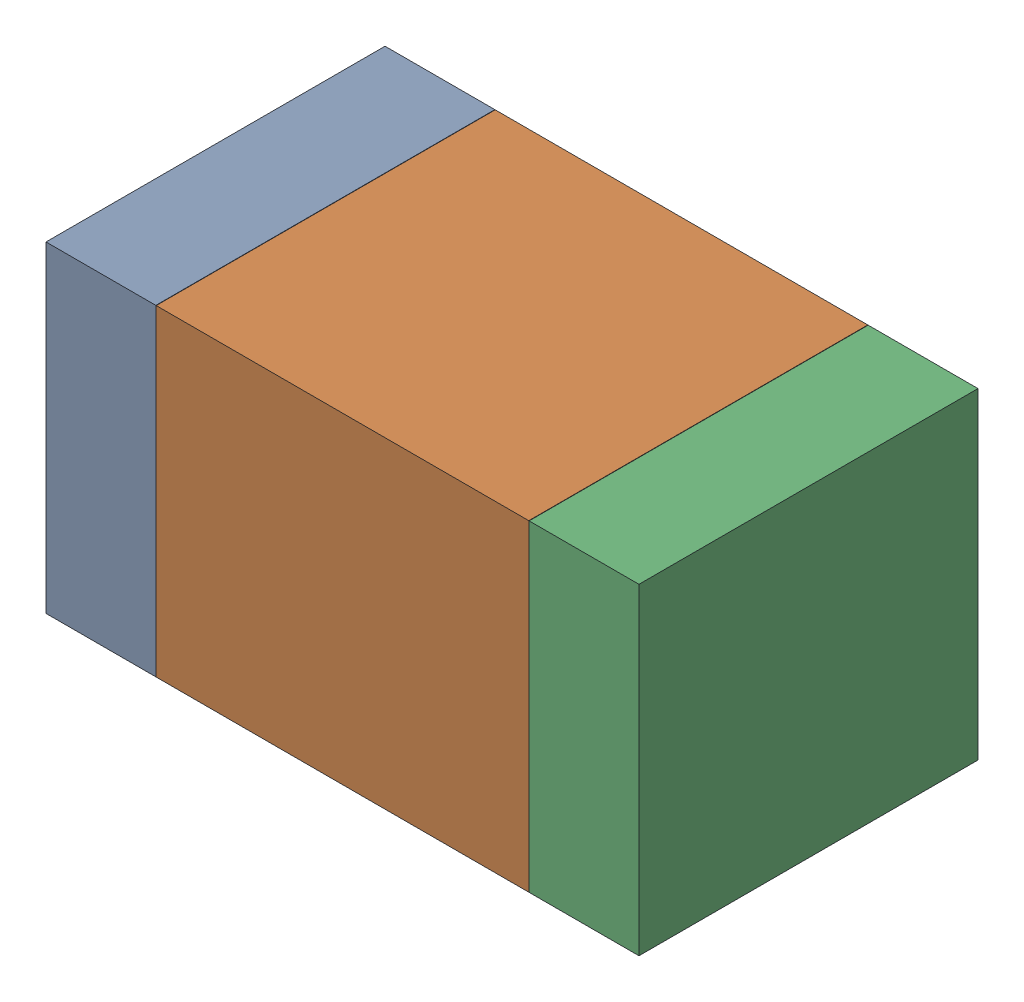
SolidWorks assembly R36, configuration Default. Lengths in mm.
Overall size (1.75 0.95 1).
6 component instances, 2 part files, 0 mates.
Components (placement in the parent):
- 6575498272-1: 6575498272 [Default] at (43.3565 24.638 0) size (0.32 0.95 1)
  - Extruded_8-1: Extruded_8 [Default] at origin size (0.32 0.95 1)
- 6575498112-1: 6575498112 [Default] at (44.069 24.638 0) size (1.1 0.95 1)
  - Extruded_9-1: Extruded_9 [Default] at origin size (1.1 0.95 1)
- 6575498272-2: 6575498272 [Default] at (44.7815 24.638 0) size (0.32 0.95 1)
  - Extruded_8-1: Extruded_8 [Default] at origin size (0.32 0.95 1)
